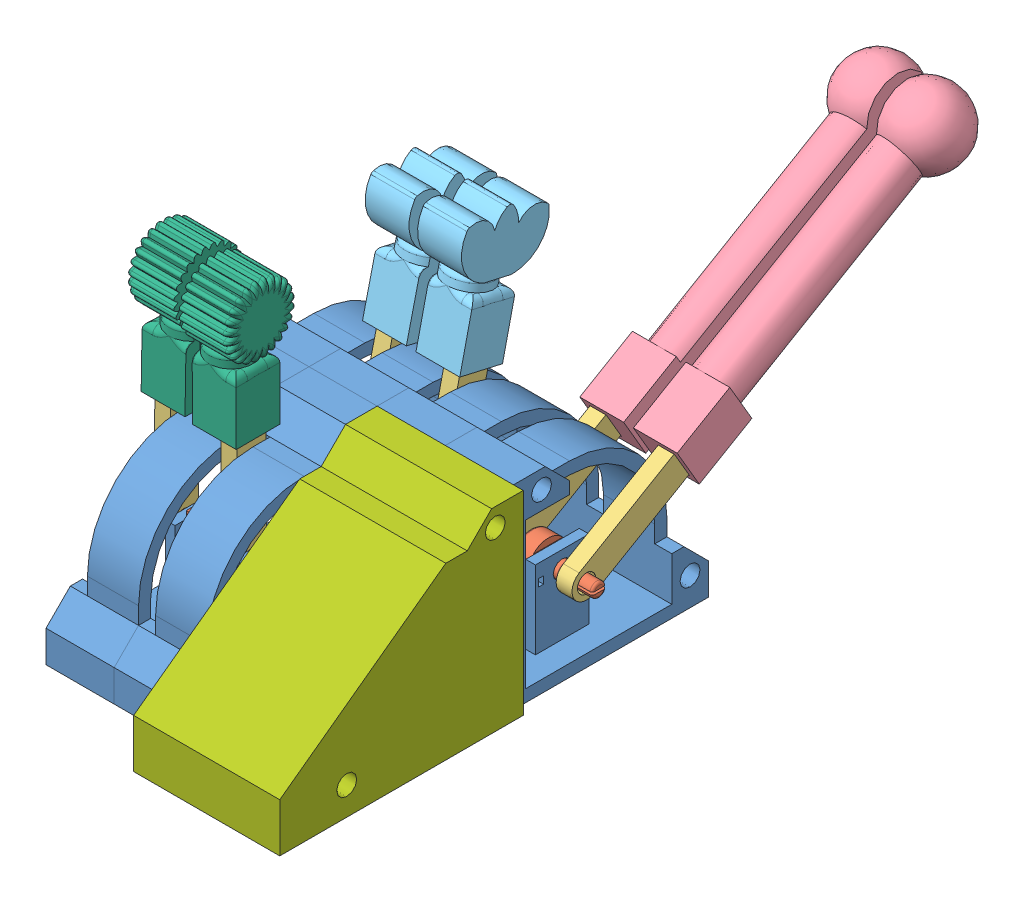
SolidWorks assembly throttle_quadrant_module, configuration По умолчанию. Lengths in mm.
Overall size (125.26 136.41 297.26).
25 component instances, 7 part files, 60 mates.
Components (placement in the parent):
- throttle_quadrant_axis_module_throttle_quadrant01a-1: throttle_quadrant_axis_module_throttle_quadrant01a [По умолчанию] at origin size (28 80 80)
- 16K1-B10K-1: 16K1-B10K [По умолчанию] at (5.1 0 0) x (0 -1 0) z (0 0 1) size (20 28.16 16.3)
- throttle_quadrant_axis_module_slider_throttle_quadrant02a-1: throttle_quadrant_axis_module_slider_throttle_quadrant02a [По умолчанию] at (28 0 0) x (0 0.222506 0.974931) z (0 -0.974931 0.222506) size (12 6.5 71)
- throttle_quadrant_axis_module_throttle_quadrant01a-2: throttle_quadrant_axis_module_throttle_quadrant01a [По умолчанию] at (28 0 0) size (28 80 80)
- 16K1-B10K-2: 16K1-B10K [По умолчанию] at (33.1 0 0) x (0 -1 0) z (0 0 1) size (20 28.16 16.3)
- throttle_quadrant_axis_module_throttle_quadrant01a-4: throttle_quadrant_axis_module_throttle_quadrant01a [По умолчанию] at (56 0 0) size (28 80 80)
- throttle_quadrant_axis_module_slider_throttle_quadrant02a-2: throttle_quadrant_axis_module_slider_throttle_quadrant02a [По умолчанию] at (56 0 0) x (0 0.863825 0.503792) z (0 -0.503792 0.863825) size (12 6.5 71)
- throttle_quadrant_axis_module_slider_throttle_quadrant02a-3: throttle_quadrant_axis_module_slider_throttle_quadrant02a [По умолчанию] at (84 0 0) x (0 0.863572 0.504225) z (0 -0.504225 0.863572) size (12 6.5 71)
- 16K1-B10K-3: 16K1-B10K [По умолчанию] at (61.1 0 0) x (0 -1 0) z (0 0 1) size (20 28.16 16.3)
- mi8_throttle-1: mi8_throttle [По умолчанию] at (69 29.1657 -49.5546) x (1 0 0) z (0 0.863572 0.504225) size (23.51 140 30)
- mi8_throttle-2: mi8_throttle [По умолчанию] at (65 29.1408 -49.5692) x (-1 0 0) z (0 -0.863825 -0.503792) size (23.51 140 30)
- throttle_quadrant_axis_module_throttle_quadrant01a-5: throttle_quadrant_axis_module_throttle_quadrant01a [По умолчанию] at (-28 0 0) size (28 80 80)
- 16K1-B10K-4: 16K1-B10K [По умолчанию] at (-22.9 0 0) x (0 -1 0) z (0 0 1) size (20 28.16 16.3)
- throttle_quadrant_axis_module_slider_throttle_quadrant02a-4: throttle_quadrant_axis_module_slider_throttle_quadrant02a [По умолчанию] x (0 0.23184 0.972754) z (0 -0.972754 0.23184) size (12 6.5 71)
- prop_knob-1: prop_knob [По умолчанию] at (8.5 55.9797 -13.1363) x (-1 0 0) z (0 -0.23184 -0.972754) size (18 54.43 36.33)
- prop_knob-2: prop_knob [По умолчанию] at (12.5 56.0141 -12.9891) x (1 0 0) z (0 0.222506 0.974931) size (18 54.43 36.33)
- throttle_quadrant_axis_module_throttle_quadrant01a-6: throttle_quadrant_axis_module_throttle_quadrant01a [По умолчанию] at (28 0 60) x (-1 0 0) z (0 0 -1) size (28 80 80)
- throttle_quadrant_axis_module_throttle_quadrant01a-7: throttle_quadrant_axis_module_throttle_quadrant01a [По умолчанию] at (0 0 60) x (-1 0 0) z (0 0 -1) size (28 80 80)
- 16K1-B10K-5: 16K1-B10K [По умолчанию] at (22.9 0 60) x (0 1 0) z (0 0 1) size (20 28.16 16.3)
- 16K1-B10K-6: 16K1-B10K [По умолчанию] at (-5.1 0 60) x (0 1 0) z (0 0 1) size (20 28.16 16.3)
- throttle_quadrant_axis_module_slider_throttle_quadrant02a-5: throttle_quadrant_axis_module_slider_throttle_quadrant02a [По умолчанию] at (0 0 60) x (0 0.003723 -0.999993) z (0 -0.999993 -0.003723) size (12 6.5 71)
- throttle_quadrant_axis_module_slider_throttle_quadrant02a-6: throttle_quadrant_axis_module_slider_throttle_quadrant02a [По умолчанию] at (-28 0 60) x (0 -0.01713 -0.999853) z (0 -0.999853 0.01713) size (12 6.5 71)
- mix_knob-1: mix_knob [По умолчанию] at (-8.5 57.4989 60.4141) x (1 0 0) z (0 -0.003723 0.999993) size (20 56.24 28.48)
- mix_knob-2: mix_knob [По умолчанию] at (-12.5 57.495 59.215) x (-1 0 0) z (0 -0.01713 -0.999853) size (20 56.24 28.48)
- switch_panel2-1: switch_panel2 [По умолчанию] at (28 -30 30) size (60 80 100)
Mates (geometry in assembly coordinates):
- Concentric1: concentric anti-aligned: cylinder of throttle_quadrant_axis_module_throttle_quadrant01a-1 through (14 0 0) axis (1 0 0) radius 3.7; cylinder of 16K1-B10K-1 through (20.4 0 0) axis (-1 0 0) radius 3.35
- Coincident1: coincident anti-aligned: plane of throttle_quadrant_axis_module_throttle_quadrant01a-1 through (14 0 0) normal (-1 0 0); plane of 16K1-B10K-1 through (14 0 0) normal (1 0 0)
- Concentric2: concentric anti-aligned: cylinder of 16K1-B10K-1 through (33.2 0 0) axis (-1 0 0) radius 2.9; cylinder of throttle_quadrant_axis_module_slider_throttle_quadrant02a-1 through (21.5 0 0) axis (1 0 0) radius 3.75
- Distance2: distance = 0.5 mm anti-aligned: plane of throttle_quadrant_axis_module_slider_throttle_quadrant02a-1 through (21.5 0 0) normal (-1 0 0); plane of throttle_quadrant_axis_module_throttle_quadrant01a-1 through (21 0 0) normal (1 0 0)
- Concentric3: concentric aligned: cylinder of throttle_quadrant_axis_module_throttle_quadrant01a-1 through (0 42.5 18.5) axis (1 0 0) radius 4.1; cylinder of throttle_quadrant_axis_module_throttle_quadrant01a-2 through (28 42.5 18.5) axis (1 0 0) radius 4.1
- Concentric4: concentric aligned: cylinder of throttle_quadrant_axis_module_throttle_quadrant01a-1 through (0 -18.5 -42.5) axis (1 0 0) radius 4.1; cylinder of throttle_quadrant_axis_module_throttle_quadrant01a-2 through (28 -18.5 -42.5) axis (1 0 0) radius 4.1
- Coincident5: coincident anti-aligned: plane of throttle_quadrant_axis_module_throttle_quadrant01a-1 through (28 0 0) normal (1 0 0); plane of throttle_quadrant_axis_module_throttle_quadrant01a-2 through (28 0 0) normal (-1 0 0)
- Concentric5: concentric anti-aligned: cylinder of throttle_quadrant_axis_module_throttle_quadrant01a-2 through (42 0 0) axis (1 0 0) radius 3.7; cylinder of 16K1-B10K-2 through (48.4 0 0) axis (-1 0 0) radius 3.35
- Coincident6: coincident anti-aligned: plane of throttle_quadrant_axis_module_throttle_quadrant01a-2 through (42 0 0) normal (-1 0 0); plane of 16K1-B10K-2 through (42 0 0) normal (1 0 0)
- Concentric8: concentric aligned: cylinder of throttle_quadrant_axis_module_throttle_quadrant01a-2 through (28 42.5 18.5) axis (1 0 0) radius 4.1; cylinder of throttle_quadrant_axis_module_throttle_quadrant01a-4 through (56 42.5 18.5) axis (1 0 0) radius 4.1
- Concentric9: concentric aligned: cylinder of throttle_quadrant_axis_module_throttle_quadrant01a-2 through (28 -18.5 -42.5) axis (1 0 0) radius 4.1; cylinder of throttle_quadrant_axis_module_throttle_quadrant01a-4 through (56 -18.5 -42.5) axis (1 0 0) radius 4.1
- Coincident8: coincident anti-aligned: plane of throttle_quadrant_axis_module_throttle_quadrant01a-2 through (56 0 0) normal (1 0 0); plane of throttle_quadrant_axis_module_throttle_quadrant01a-4 through (56 0 0) normal (-1 0 0)
- Concentric10: concentric anti-aligned: cylinder of 16K1-B10K-2 through (61.2 0 0) axis (-1 0 0) radius 2.9; cylinder of throttle_quadrant_axis_module_slider_throttle_quadrant02a-2 through (49.5 0 0) axis (1 0 0) radius 3.75
- Concentric11: concentric anti-aligned: cylinder of throttle_quadrant_axis_module_throttle_quadrant01a-4 through (70 0 0) axis (1 0 0) radius 3.7; cylinder of 16K1-B10K-3 through (76.4 0 0) axis (-1 0 0) radius 3.35
- Coincident10: coincident anti-aligned: plane of throttle_quadrant_axis_module_throttle_quadrant01a-4 through (70 0 0) normal (-1 0 0); plane of 16K1-B10K-3 through (70 0 0) normal (1 0 0)
- Concentric12: concentric anti-aligned: cylinder of throttle_quadrant_axis_module_slider_throttle_quadrant02a-3 through (77.5 0 0) axis (1 0 0) radius 3.75; cylinder of 16K1-B10K-3 through (89.2 0 0) axis (-1 0 0) radius 2.9
- Distance4: distance = 0.5 mm anti-aligned: plane of throttle_quadrant_axis_module_slider_throttle_quadrant02a-2 through (49.5 0 0) normal (-1 0 0); plane of throttle_quadrant_axis_module_throttle_quadrant01a-2 through (49 0 0) normal (1 0 0)
- Distance5: distance = 0.5 mm anti-aligned: plane of throttle_quadrant_axis_module_slider_throttle_quadrant02a-3 through (77.5 0 0) normal (-1 0 0); plane of throttle_quadrant_axis_module_throttle_quadrant01a-4 through (77 0 0) normal (1 0 0)
- Coincident13: coincident anti-aligned: plane of throttle_quadrant_axis_module_slider_throttle_quadrant02a-3 through (77.5 0 0) normal (-1 0 0); plane of mi8_throttle-1 through (77.5 27.5932 -59.1575) normal (1 0 0)
- Coincident14: coincident anti-aligned: plane of throttle_quadrant_axis_module_slider_throttle_quadrant02a-3 through (77.5 27.5932 -59.1575) normal (0 0.504225 -0.863572); plane of mi8_throttle-1 through (69 32.9474 -56.0313) normal (0 -0.504225 0.863572)
- Coincident15: coincident anti-aligned: plane of throttle_quadrant_axis_module_slider_throttle_quadrant02a-3 through (77.5 -5.1814 -3.0254) normal (0 -0.863572 -0.504225); plane of mi8_throttle-1 through (77.5 27.5932 -59.1575) normal (0 0.863572 0.504225)
- Coincident16: coincident anti-aligned: plane of throttle_quadrant_axis_module_slider_throttle_quadrant02a-2 through (49.5 0 0) normal (-1 0 0); plane of mi8_throttle-2 through (49.5 38.275 -52.9243) normal (1 0 0)
- Coincident17: coincident anti-aligned: plane of throttle_quadrant_axis_module_slider_throttle_quadrant02a-2 through (49.5 27.5636 -59.1714) normal (0 0.503792 -0.863825); plane of mi8_throttle-2 through (65 32.9193 -56.0479) normal (0 -0.503792 0.863825)
- Coincident18: coincident anti-aligned: plane of throttle_quadrant_axis_module_slider_throttle_quadrant02a-2 through (49.5 -5.1829 -3.0228) normal (0 -0.863825 -0.503792); plane of mi8_throttle-2 through (56.5 27.5636 -59.1714) normal (0 0.863825 0.503792)
- Concentric14: concentric aligned: cylinder of throttle_quadrant_axis_module_throttle_quadrant01a-1 through (0 42.5 18.5) axis (1 0 0) radius 4.1; cylinder of throttle_quadrant_axis_module_throttle_quadrant01a-5 through (-28 42.5 18.5) axis (1 0 0) radius 4.1
- Concentric15: concentric aligned: cylinder of throttle_quadrant_axis_module_throttle_quadrant01a-1 through (0 -18.5 -42.5) axis (1 0 0) radius 4.1; cylinder of throttle_quadrant_axis_module_throttle_quadrant01a-5 through (-28 -18.5 -42.5) axis (1 0 0) radius 4.1
- Coincident19: coincident anti-aligned: plane of throttle_quadrant_axis_module_throttle_quadrant01a-1 through (0 0 0) normal (-1 0 0); plane of throttle_quadrant_axis_module_throttle_quadrant01a-5 through (0 0 0) normal (1 0 0)
- Concentric16: concentric anti-aligned: cylinder of throttle_quadrant_axis_module_throttle_quadrant01a-5 through (-14 0 0) axis (1 0 0) radius 3.7; cylinder of 16K1-B10K-4 through (-7.6 0 0) axis (-1 0 0) radius 3.35
- Coincident20: coincident anti-aligned: plane of throttle_quadrant_axis_module_throttle_quadrant01a-5 through (-14 0 0) normal (-1 0 0); plane of 16K1-B10K-4 through (-14 0 0) normal (1 0 0)
- Concentric17: concentric anti-aligned: cylinder of 16K1-B10K-4 through (5.2 0 0) axis (-1 0 0) radius 2.9; cylinder of throttle_quadrant_axis_module_slider_throttle_quadrant02a-4 through (-6.5 0 0) axis (1 0 0) radius 3.75
- Distance6: distance = 0.5 mm anti-aligned: plane of throttle_quadrant_axis_module_slider_throttle_quadrant02a-4 through (-6.5 0 0) normal (-1 0 0); plane of throttle_quadrant_axis_module_throttle_quadrant01a-5 through (-7 0 0) normal (1 0 0)
- Coincident22: coincident anti-aligned: plane of throttle_quadrant_axis_module_slider_throttle_quadrant02a-1; plane of prop_knob-2
- Coincident23: coincident anti-aligned: plane of throttle_quadrant_axis_module_slider_throttle_quadrant02a-1; plane of prop_knob-2
- Coincident24: coincident anti-aligned: plane of throttle_quadrant_axis_module_slider_throttle_quadrant02a-1 through (28 0 0) normal (1 0 0); plane of prop_knob-2 through (28 61.9465 -20.7024) normal (-1 0 0)
- Coincident25: coincident anti-aligned: plane of throttle_quadrant_axis_module_slider_throttle_quadrant02a-4 through (-6.5 61.838 -20.9061) normal (0 0.972754 -0.23184); plane of prop_knob-1 through (8.5 63.2754 -14.8751) normal (0 -0.972754 0.23184)
- Coincident32: coincident anti-aligned: plane of throttle_quadrant_axis_module_slider_throttle_quadrant02a-4 through (0 0 0) normal (1 0 0); plane of prop_knob-1 through (0 64.7128 -8.844) normal (-1 0 0)
- Coincident33: coincident anti-aligned: plane of throttle_quadrant_axis_module_slider_throttle_quadrant02a-4 through (-6.5 -1.391 -5.8365) normal (0 -0.23184 -0.972754); plane of prop_knob-1 through (0 61.838 -20.9061) normal (0 0.23184 0.972754)
- Coincident34: coincident anti-aligned: line of throttle_quadrant_axis_module_throttle_quadrant01a-4 through (56 50 30) axis (1 0 0); line of throttle_quadrant_axis_module_throttle_quadrant01a-6 through (28 50 30) axis (-1 0 0)
- Coincident35: coincident anti-aligned: line of throttle_quadrant_axis_module_throttle_quadrant01a-4 through (84 -30 30) axis (-1 0 0); line of throttle_quadrant_axis_module_throttle_quadrant01a-6 through (0 -30 30) axis (1 0 0)
- Coincident37: coincident anti-aligned: line of throttle_quadrant_axis_module_throttle_quadrant01a-5 through (0 50 17) axis (0 0 1); line of throttle_quadrant_axis_module_throttle_quadrant01a-6 through (0 50 43) axis (0 0 -1)
- Coincident38: coincident anti-aligned: plane of throttle_quadrant_axis_module_throttle_quadrant01a-6 through (0 0 60) normal (-1 0 0); plane of throttle_quadrant_axis_module_throttle_quadrant01a-7 through (0 0 60) normal (1 0 0)
- Concentric18: concentric aligned: cylinder of throttle_quadrant_axis_module_throttle_quadrant01a-6 through (28 42.5 41.5) axis (-1 0 0) radius 4.1; cylinder of throttle_quadrant_axis_module_throttle_quadrant01a-7 through (0 42.5 41.5) axis (-1 0 0) radius 4.1
- Concentric19: concentric aligned: cylinder of throttle_quadrant_axis_module_throttle_quadrant01a-6 through (28 -18.5 102.5) axis (-1 0 0) radius 4.1; cylinder of throttle_quadrant_axis_module_throttle_quadrant01a-7 through (0 -18.5 102.5) axis (-1 0 0) radius 4.1
- Concentric20: concentric anti-aligned: cylinder of throttle_quadrant_axis_module_throttle_quadrant01a-7 through (-14 0 60) axis (-1 0 0) radius 3.7; cylinder of 16K1-B10K-6 through (-20.4 0 60) axis (1 0 0) radius 3.35
- Coincident39: coincident anti-aligned: plane of throttle_quadrant_axis_module_throttle_quadrant01a-7 through (-14 0 60) normal (1 0 0); plane of 16K1-B10K-6 through (-14 0 60) normal (-1 0 0)
- Concentric21: concentric anti-aligned: cylinder of throttle_quadrant_axis_module_throttle_quadrant01a-6 through (14 0 60) axis (-1 0 0) radius 3.7; cylinder of 16K1-B10K-5 through (7.6 0 60) axis (1 0 0) radius 3.35
- Coincident40: coincident anti-aligned: plane of throttle_quadrant_axis_module_throttle_quadrant01a-6 through (14 0 60) normal (1 0 0); plane of 16K1-B10K-5 through (14 0 60) normal (-1 0 0)
- Concentric22: concentric anti-aligned: cylinder of 16K1-B10K-6 through (-33.2 0 60) axis (1 0 0) radius 2.9; cylinder of throttle_quadrant_axis_module_slider_throttle_quadrant02a-6 through (-21.5 0 60) axis (-1 0 0) radius 3.75
- Distance7: distance = 0.5 mm anti-aligned: plane of throttle_quadrant_axis_module_slider_throttle_quadrant02a-6 through (-21.5 0 60) normal (1 0 0); plane of throttle_quadrant_axis_module_throttle_quadrant01a-7 through (-21 0 60) normal (-1 0 0)
- Concentric23: concentric anti-aligned: cylinder of 16K1-B10K-5 through (-5.2 0 60) axis (1 0 0) radius 2.9; cylinder of throttle_quadrant_axis_module_slider_throttle_quadrant02a-5 through (6.5 0 60) axis (-1 0 0) radius 3.75
- Distance8: distance = 0.5 mm anti-aligned: plane of throttle_quadrant_axis_module_slider_throttle_quadrant02a-5 through (6.5 0 60) normal (1 0 0); plane of throttle_quadrant_axis_module_throttle_quadrant01a-6 through (7 0 60) normal (-1 0 0)
- Coincident43: coincident anti-aligned: plane of throttle_quadrant_axis_module_slider_throttle_quadrant02a-6 through (-21.5 65.0932 64.8857) normal (0 0.999853 -0.01713); plane of mix_knob-2 through (-12.5 64.9939 59.0865) normal (0 -0.999853 0.01713)
- Coincident44: coincident anti-aligned: plane of throttle_quadrant_axis_module_slider_throttle_quadrant02a-6 through (-28 0 60) normal (-1 0 0); plane of mix_knob-2 through (-28 65.1001 65.2856) normal (1 0 0)
- Coincident45: coincident anti-aligned: plane of throttle_quadrant_axis_module_slider_throttle_quadrant02a-6 through (-21.5 64.8877 52.8875) normal (0 -0.01713 -0.999853); plane of mix_knob-2 through (-21 64.8877 52.8875) normal (0 0.01713 0.999853)
- Coincident46: coincident anti-aligned: plane of throttle_quadrant_axis_module_slider_throttle_quadrant02a-5 through (6.5 64.9772 66.2419) normal (0 0.999993 0.003723); plane of mix_knob-1 through (-8.5 64.9988 60.442) normal (0 -0.999993 -0.003723)
- Coincident47: coincident anti-aligned: plane of throttle_quadrant_axis_module_slider_throttle_quadrant02a-5 through (0 0 60) normal (-1 0 0); plane of mix_knob-1 through (0 65.0219 54.242) normal (1 0 0)
- Coincident48: coincident anti-aligned: plane of throttle_quadrant_axis_module_slider_throttle_quadrant02a-5 through (6.5 65.0219 54.242) normal (0 0.003723 -0.999993); plane of mix_knob-1 through (0 65.0219 54.242) normal (0 -0.003723 0.999993)
- Concentric24: concentric aligned: cylinder of throttle_quadrant_axis_module_throttle_quadrant01a-6 through (28 42.5 41.5) axis (-1 0 0) radius 4.1; cylinder of switch_panel2-1 through (88 42.5 41.5) axis (-1 0 0) radius 4.1
- Concentric25: concentric aligned: cylinder of throttle_quadrant_axis_module_throttle_quadrant01a-6 through (28 -18.5 102.5) axis (-1 0 0) radius 4.1; cylinder of switch_panel2-1 through (88 -18.5 102.5) axis (-1 0 0) radius 4.1
- Coincident52: coincident anti-aligned: plane of throttle_quadrant_axis_module_throttle_quadrant01a-6 through (28 0 60) normal (1 0 0); plane of switch_panel2-1 through (28 -30 30) normal (-1 0 0)
